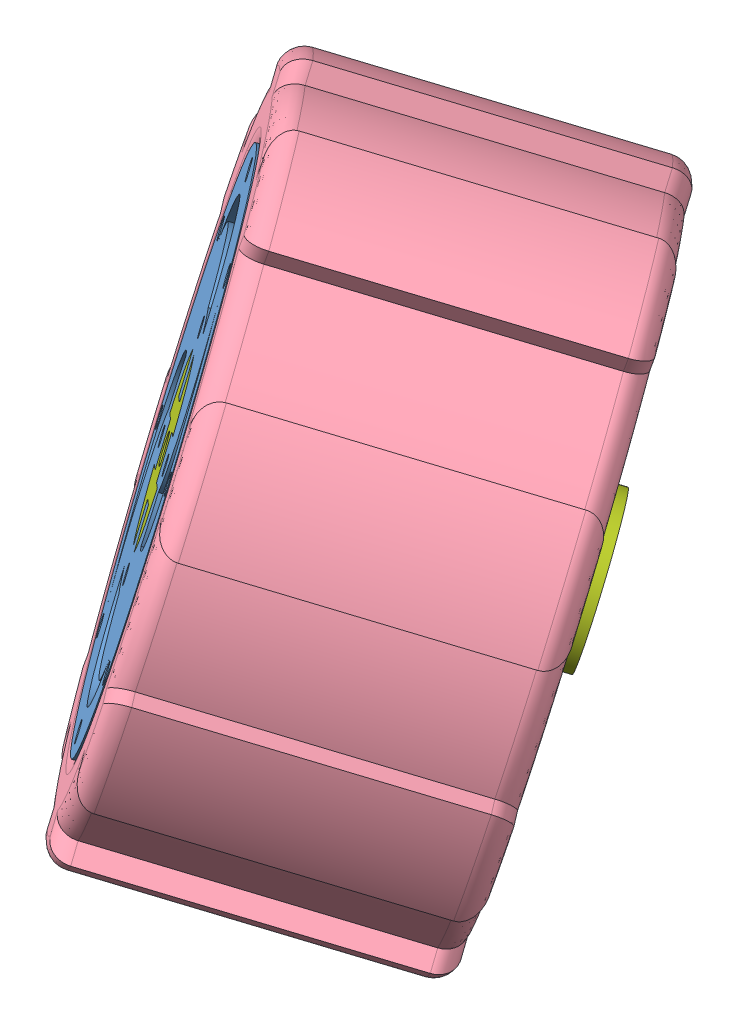
SolidWorks assembly Wheel_Assembly, configuration Default. Lengths in mm.
Overall size (170.87 223.11 227.74).
7 component instances, 7 part files, 18 mates.
Components (placement in the parent):
- Outside Ring_2-1: Outside Ring_2 [Default] at (-147.5523 543.3868 279.3934) x (0.124018 -0.837383 0.532362) z (0.766517 -0.259854 -0.587306) size (120 120 10)
- Motor_Connector_Ring_1-1: Motor_Connector_Ring_1 [Default] at (-101.5613 527.7956 244.155) x (-0.124018 0.837383 -0.532362) z (0.766517 -0.259854 -0.587306) size (58 58 15)
- Motor_Connector_Ring_2-1: Motor_Connector_Ring_2 [Default] at (-136.0545 539.489 270.5838) x (-0.124018 0.837383 -0.532362) z (0.766517 -0.259854 -0.587306) size (58 58 15)
- Tire-2: Tire [Default] at (-155.2174 545.9854 285.2664) x (-0.035485 0.895953 -0.442729) z (-0.641243 -0.3602 -0.677542) size (160.88 80.88 160.88)
- Inner Ring-1: Inner Ring [Default] at (-113.059 531.6934 252.9646) x (-0.124018 0.837383 -0.532362) z (0.766517 -0.259854 -0.587306) size (120 120 30)
- Outside Ring_1-1: Outside Ring_1 [Default] at (-93.8961 525.197 238.282) x (-0.124018 0.837383 -0.532362) z (0.766517 -0.259854 -0.587306) size (120 120 10)
- Wheel_Brushing_Connector-1: Wheel_Brushing_Connector [Default] at (-89.8681 523.8315 235.1957) x (0.630136 0.4809 0.609642) z (0.124018 -0.837383 0.532362) size (38.73 85.25 38.73)
Mates (geometry in assembly coordinates):
- Coincident38: coincident anti-aligned: plane of Motor_Connector_Ring-1 through (-101.5613 527.7956 244.155) normal (0.766517 -0.259854 -0.587306); plane of Outside Ring_1-1 through (-101.5613 527.7956 244.155) normal (-0.766517 0.259854 0.587306)
- Coincident39: coincident aligned: plane of Motor_Connector_Ring-1 through (-111.8188 523.3196 258.2882) normal (-0.124018 0.837383 -0.532362); plane of Outside Ring_1-1 through (-100.3211 519.4218 249.4786) normal (-0.124018 0.837383 -0.532362)
- Coincident40: coincident aligned: plane of Motor_Connector_Ring-1 through (-106.7577 536.5024 259.061) normal (-0.630136 -0.4809 -0.609642); plane of Outside Ring_1-1 through (-95.2599 532.6046 250.2514) normal (-0.630136 -0.4809 -0.609642)
- Coincident42: coincident anti-aligned: plane of Motor_Connector_Ring-1 through (-113.059 531.6934 252.9646) normal (-0.766517 0.259854 0.587306); plane of Inner Ring-1 through (-113.059 531.6934 252.9646) normal (0.766517 -0.259854 -0.587306)
- Coincident43: coincident aligned: plane of Motor_Connector_Ring-1 through (-119.3604 526.8844 246.8682) normal (0.630136 0.4809 0.609642); plane of Inner Ring-1 through (-142.3559 534.68 264.4874) normal (0.630136 0.4809 0.609642)
- Coincident44: coincident aligned: plane of Motor_Connector_Ring-1 through (-114.2992 540.0672 247.641) normal (0.124018 -0.837383 0.532362); plane of Inner Ring-1 through (-137.2947 547.8628 265.2602) normal (0.124018 -0.837383 0.532362)
- Coincident45: coincident anti-aligned: plane of Motor_Connector_Ring_2-1 through (-136.0545 539.489 270.5838) normal (0.766517 -0.259854 -0.587306); plane of Inner Ring-1 through (-136.0545 539.489 270.5838) normal (-0.766517 0.259854 0.587306)
- Coincident46: coincident aligned: plane of Motor_Connector_Ring_2-1 through (-153.8536 538.5778 273.2969) normal (0.630136 0.4809 0.609642); plane of Inner Ring-1 through (-142.3559 534.68 264.4874) normal (0.630136 0.4809 0.609642)
- Coincident47: coincident aligned: plane of Motor_Connector_Ring_2-1 through (-148.7925 551.7606 274.0697) normal (0.124018 -0.837383 0.532362); plane of Inner Ring-1 through (-137.2947 547.8628 265.2602) normal (0.124018 -0.837383 0.532362)
- Coincident48: coincident aligned: plane of Outside Ring_2-1 through (-156.4576 554.3592 279.9428) normal (0.124018 -0.837383 0.532362); plane of Motor_Connector_Ring_2-1 through (-148.7925 551.7606 274.0697) normal (0.124018 -0.837383 0.532362)
- Coincident49: coincident anti-aligned: plane of Outside Ring_2-1 through (-147.5523 543.3868 279.3934) normal (0.766517 -0.259854 -0.587306); plane of Motor_Connector_Ring_2-1 through (-147.5523 543.3868 279.3934) normal (-0.766517 0.259854 0.587306)
- Coincident50: coincident aligned: plane of Outside Ring_2-1 through (-148.9161 550.7944 291.3628) normal (-0.630136 -0.4809 -0.609642); plane of Motor_Connector_Ring_2-1 through (-141.2509 548.1958 285.4898) normal (-0.630136 -0.4809 -0.609642)
- Parallel5: parallel anti-aligned: plane of Outside Ring_2-1 through (-147.5523 543.3868 279.3934) normal (0.766517 -0.259854 -0.587306); plane of Tire-2 through (-143.7197 542.0875 276.4568) normal (-0.766517 0.259854 0.587306)
- Coincident53: coincident aligned: plane of Outside Ring_2-1 through (-155.2174 545.9854 285.2664) normal (-0.766517 0.259854 0.587306); plane of Tire-2 through (-155.2174 545.9854 285.2664) normal (-0.766517 0.259854 0.587306)
- Concentric21: concentric anti-aligned: cylinder of Outside Ring_2-1 through (-155.2174 545.9854 285.2664) axis (0.766517 -0.259854 -0.587306) radius 60; cylinder of Tire-2 through (-147.5523 543.3868 279.3934) axis (-0.766517 0.259854 0.587306) radius 60
- Coincident55: coincident anti-aligned: plane of Outside Ring_1-1 through (-100.9412 523.6087 246.8168) normal (0.124018 -0.837383 0.532362); plane of Wheel_Brushing_Connector-1 through (-92.5095 520.7503 240.3565) normal (-0.124018 0.837383 -0.532362)
- Coincident56: coincident anti-aligned: plane of Motor_Connector_Ring-1 through (-119.3604 526.8844 246.8682) normal (0.630136 0.4809 0.609642); plane of Wheel_Brushing_Connector-1 through (-99.4309 520.1282 231.5982) normal (-0.630136 -0.4809 -0.609642)
- Coincident60: coincident aligned: plane of Outside Ring_2-1 through (-155.2174 545.9854 285.2664) normal (-0.766517 0.259854 0.587306); plane of Wheel_Brushing_Connector-1 through (-155.2174 545.9854 285.2664) normal (-0.766517 0.259854 0.587306)
